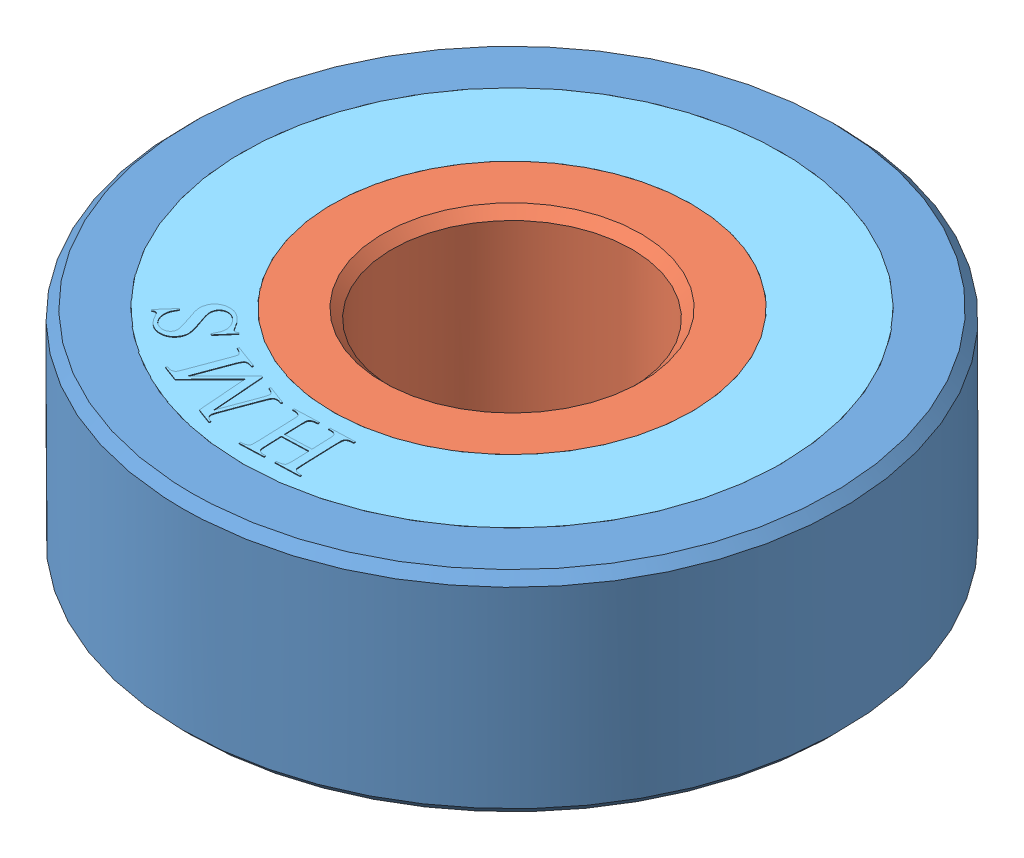
SolidWorks assembly Ball_Bearing_608_2RSH, configuration Default. Lengths in mm.
Overall size (25.49 7.53 25.49).
14 component instances, 5 part files, 0 mates.
Components (placement in the parent):
- Deep Groove Ball Bearing 608-2RSH 8mm I.D, 22mm O.D.stp-1: Deep Groove Ball Bearing 608-2RSH 8mm I.D, 22mm O.D.stp [Default] at origin size (25.49 7.53 25.49)
  - outer race.stp-1: outer race.stp [Default] at origin size (22 7 22)
  - inner race.stp-1: inner race.stp [Default] x (0.998045 0 -0.0625) z (0.0625 0 0.998045) size (12 7 12)
  - retainer.stp-1: retainer.stp [Default] x (-0.325178 0 -0.945653) z (-0.945653 0 0.325178) size (20.06 6 20.06)
  - ball.stp-1: ball.stp [Default] at (-6.7396 0 -3.2906) x (-0.584318 0.768334 -0.261218) z (-0.624567 -0.631294 -0.459765) size (5 5 5)
  - ball.stp-2: ball.stp [Default] at (3.2906 0 -6.7396) x (-0.938425 0.011388 -0.345297) z (0.106265 -0.94149 -0.319851) size (5 5 5)
  - ball.stp-3: ball.stp [Default] at (-2.4388 0 -7.0924) x (-0.938425 0.011388 -0.345297) z (0.106265 -0.94149 -0.319851) size (5 5 5)
  - ball.stp-4: ball.stp [Default] at (7.0924 0 -2.4388) x (-0.938425 0.011388 -0.345297) z (0.106265 -0.94149 -0.319851) size (5 5 5)
  - ball.stp-5: ball.stp [Default] at (-7.0924 0 2.4388) x (-0.938425 0.011388 -0.345297) z (0.106265 -0.94149 -0.319851) size (5 5 5)
  - ball.stp-6: ball.stp [Default] at (-3.2906 0 6.7396) x (-0.938425 0.011388 -0.345297) z (0.106265 -0.94149 -0.319851) size (5 5 5)
  - ball.stp-7: ball.stp [Default] at (2.4388 0 7.0924) x (-0.938425 0.011388 -0.345297) z (0.106265 -0.94149 -0.319851) size (5 5 5)
  - ball.stp-8: ball.stp [Default] at (6.7396 0 3.2906) x (-0.938425 0.011388 -0.345297) z (0.106265 -0.94149 -0.319851) size (5 5 5)
  - cover.stp-1: cover.stp [Default] at (0 -3.25 0) x (0.969563 0 0.244841) z (-0.244841 0 0.969563) size (18 0.57 18)
  - cover.stp-2: cover.stp [Default] at (0 3.25 0) x (-0.15753 0 -0.987514) z (-0.987514 0 0.15753) size (18 0.57 18)
